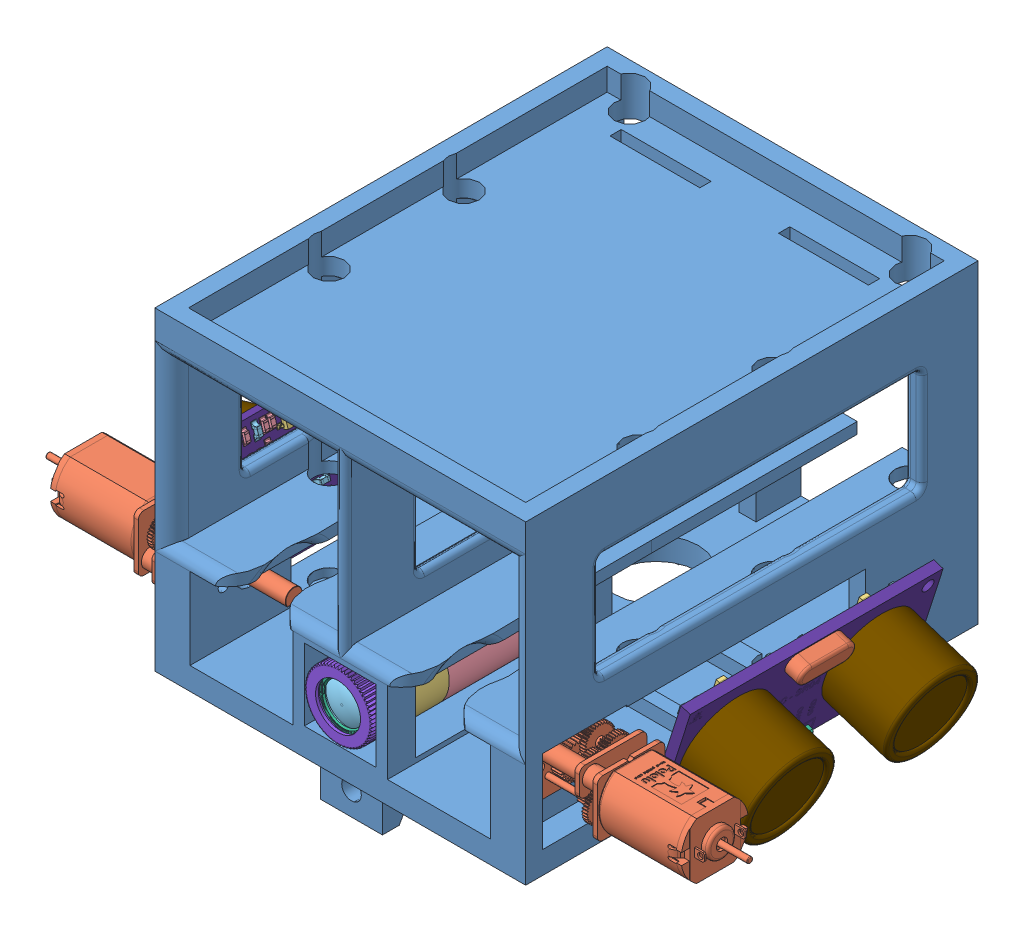
SolidWorks assembly ZumoPlatform, configuration Default. Lengths in mm.
Overall size (124.9 63 80.53).
123 component instances, 24 part files, 37 mates.
Components (placement in the parent):
- Platform-1: Platform [Default] at (31.3315 31.2801 62.3209) size (66.46 63 80.5)
- micro-metal-gearmotor-1000-backshaft-1: micro-metal-gearmotor-1000-backshaft [Default] at (72.5815 44.5801 92.0709) x (0 0 1) z (-1 0 0) size (12.01 10.08 43.7)
- micro-metal-gearmotor-1000-backshaft-2: micro-metal-gearmotor-1000-backshaft [Default] at (-9.9185 44.5801 92.0709) x (0 0 1) z (1 0 0) size (12.01 10.08 43.7)
- Laser Diode Module-1: Laser Diode Module [Default] at (1.0789 32.0697 83.277) x (-0.999994 0.003569 0) z (0.003569 0.999994 0) size (12.77 59.55 13.15)
  - LD module diode mount back nut-1: LD module diode mount back nut [Default] at (-29.8165 5.6939 10.1669) size (12 16.05 12.21)
  - LD module body-1: LD module body [Default] at (-29.8165 -14.5006 10.1669) x (0.999982 0 -0.006001) z (0.006001 0 0.999982) size (12 20.05 13.08)
  - G-2 colimating lens-1: G-2 colimating lens [Default] at (-29.9063 12.9338 10.1669) size (8.06 5.78 8.06)
  - G-2 lens focusable mount-1: G-2 lens focusable mount [Default] at (-29.9063 10.9338 10.1669) x (0.993643 0 0.112577) z (-0.112577 0 0.993643) size (9.01 8.01 10.39)
  - LD module tension spring-2: LD module tension spring [Default] at (-29.8165 10.9338 10.1669) size (8.46 6.4 9.76)
  - Lens Focusing Ring-1: Lens Focusing Ring [Default] at (-29.8165 15.7939 10.1669) x (-0.998124 0 -0.061226) z (0 1 0) size (12.06 12.06 3.9)
  - Mitsubishi ML501P73 500mW 638nm Laser Diode with leads-1: Mitsubishi ML501P73 500mW 638nm Laser Diode with leads [Default] at (-29.8165 0.2494 10.1669) x (0.917172 0 0.398492) z (-0.398492 0 0.917172) size (5.58 43.98 5.49)
- slc_connector_811-s1-006-10-014101-1: slc_connector_811-s1-006-10-014101 [Default] at (46.7115 79.0101 31.9709) x (1 0 0) z (0 -1 0) size (15.24 9 2.54)
  - slc_connector_811-s1-006-10-014101_01-1: slc_connector_811-s1-006-10-014101_01 [Default] at origin size (15.24 7.5 2.54)
  - slc_connector_811-s1-006-10-014101_02-1: slc_connector_811-s1-006-10-014101_02 [Default] at origin size (1.25 4.17 1.25)
  - slc_connector_811-s1-006-10-014101_03-1: slc_connector_811-s1-006-10-014101_03 [Default] at origin size (1.25 4.17 1.25)
  - slc_connector_811-s1-006-10-014101_04-1: slc_connector_811-s1-006-10-014101_04 [Default] at origin size (1.25 4.17 1.25)
  - slc_connector_811-s1-006-10-014101_05-1: slc_connector_811-s1-006-10-014101_05 [Default] at origin size (1.25 4.17 1.25)
  - slc_connector_811-s1-006-10-014101_06-1: slc_connector_811-s1-006-10-014101_06 [Default] at origin size (1.25 4.17 1.25)
  - slc_connector_811-s1-006-10-014101_07-1: slc_connector_811-s1-006-10-014101_07 [Default] at origin size (1.25 4.17 1.25)
- slc_connector_811-s1-006-10-014101-2: slc_connector_811-s1-006-10-014101 [Default] at (15.9515 79.0101 31.9709) x (1 0 0) z (0 -1 0) size (15.24 9 2.54)
  - slc_connector_811-s1-006-10-014101_01-1: slc_connector_811-s1-006-10-014101_01 [Default] at origin size (15.24 7.5 2.54)
  - slc_connector_811-s1-006-10-014101_02-1: slc_connector_811-s1-006-10-014101_02 [Default] at origin size (1.25 4.17 1.25)
  - slc_connector_811-s1-006-10-014101_03-1: slc_connector_811-s1-006-10-014101_03 [Default] at origin size (1.25 4.17 1.25)
  - slc_connector_811-s1-006-10-014101_04-1: slc_connector_811-s1-006-10-014101_04 [Default] at origin size (1.25 4.17 1.25)
  - slc_connector_811-s1-006-10-014101_05-1: slc_connector_811-s1-006-10-014101_05 [Default] at origin size (1.25 4.17 1.25)
  - slc_connector_811-s1-006-10-014101_06-1: slc_connector_811-s1-006-10-014101_06 [Default] at origin size (1.25 4.17 1.25)
  - slc_connector_811-s1-006-10-014101_07-1: slc_connector_811-s1-006-10-014101_07 [Default] at origin size (1.25 4.17 1.25)
- HC-SR04-1: HC-SR04 [Default] at (-5.6368 33.7192 38.4111) x (0 0 1) z (-0.957373 -0.288853 0) size (45 20.53 19.69)
  - HC-SR04_HC-SR04 Ping Sensor-1: HC-SR04_HC-SR04 Ping Sensor [Default] at (22.5 10.25 -1.75) x (0 -1 0) z (0 0 1) size (20.53 45 15.35)
    - HC-SR04_PCB-1: HC-SR04_PCB [Default] at origin size (20.53 45 1.75)
    - HC-SR04_Transducer-1: HC-SR04_Transducer [Default] at (0 -13.16 13.25) x (1 0 0) z (0 -1 0) size (15.88 12 15.88)
    - HC-SR04_Transducer-2: HC-SR04_Transducer [Default] at (0 12.34 13.25) x (1 0 0) z (0 -1 0) size (15.88 12 15.88)
    - HC-SR04_14 Pin SMT-1: HC-SR04_14 Pin SMT [Default] at (0 17.5274 -0.85) x (1 0 0) z (0 1 0) size (6 1.6 8.8)
    - HC-SR04_14 Pin SMT-2: HC-SR04_14 Pin SMT [Default] at (-0.35 -18.5 -0.85) x (0 -1 0) z (1 0 0) size (6 1.6 8.8)
    - HC-SR04_14 Pin SMT-3: HC-SR04_14 Pin SMT [Default] at (0 -0.3826 -0.85) x (1 0 0) z (0 1 0) size (6 1.6 8.8)
    - HC-SR04_HC-SR04 Crystal-1: HC-SR04_HC-SR04 Crystal [Default] at (-8.3 0 1.75) x (0 -1 0) z (0 0 1) size (10 3.5 2.7)
    - HC-SR04_ssot3-1: HC-SR04_ssot3 [Default] at (-7.9706 11.2297 0) x (1 0 0) z (0 1 0) size (3 1.13 3.09)
    - HC-SR04_ssot3-2: HC-SR04_ssot3 [Default] at (-7.9706 -14.2327 0) x (1 0 0) z (0 1 0) size (3 1.13 3.09)
    - HC-SR04_MLC0603-1: HC-SR04_MLC0603 [Default] at (1.5086 11.2209 0) x (1 0 0) z (0 1 0) size (2.36 0.6 1.03)
    - HC-SR04_MLC0603-2: HC-SR04_MLC0603 [Default] at (-4.7079 -6.8438 0) x (1 0 0) z (0 1 0) size (2.36 0.6 1.03)
    - HC-SR04_MLC0603-3: HC-SR04_MLC0603 [Default] at (-8.4554 -9.9341 0) x (0 1 0) z (-1 0 0) size (2.36 0.6 1.03)
    - HC-SR04_MLC0603-4: HC-SR04_MLC0603 [Default] at (7.7901 17.1702 0) x (1 0 0) z (0 1 0) size (2.36 0.6 1.03)
    - HC-SR04_MLC0603-5: HC-SR04_MLC0603 [Default] at (-4.2399 7.0151 0) x (0 1 0) z (-1 0 0) size (2.36 0.6 1.03)
    - HC-SR04_MLC0603-6: HC-SR04_MLC0603 [Default] at (-8.2266 4.8481 0) x (1 0 0) z (0 1 0) size (2.36 0.6 1.03)
    - HC-SR04_MLC0603-7: HC-SR04_MLC0603 [Default] at (-8.276 3.0726 0) x (1 0 0) z (0 1 0) size (2.36 0.6 1.03)
    - HC-SR04_MLC0603-8: HC-SR04_MLC0603 [Default] at (-8.1718 18.0917 0) x (1 0 0) z (0 1 0) size (2.36 0.6 1.03)
    - HC-SR04_MLC0603-9: HC-SR04_MLC0603 [Default] at (-5.0505 19.9858 0) x (0 1 0) z (-1 0 0) size (2.36 0.6 1.03)
    - HC-SR04_MLC0603-10: HC-SR04_MLC0603 [Default] at (4.9221 -0.625 0) x (0 1 0) z (-1 0 0) size (2.36 0.6 1.03)
    - HC-SR04_MLC0603-11: HC-SR04_MLC0603 [Default] at (-6.3425 7.0242 0) x (0 1 0) z (-1 0 0) size (2.36 0.6 1.03)
    - HC-SR04_MLC0603-12: HC-SR04_MLC0603 [Default] at (4.867 -3.8906 0) x (0 1 0) z (-1 0 0) size (2.36 0.6 1.03)
    - HC-SR04_MLC0603-13: HC-SR04_MLC0603 [Default] at (7.7433 15.7761 0) x (1 0 0) z (0 1 0) size (2.36 0.6 1.03)
    - HC-SR04_MLC0603-14: HC-SR04_MLC0603 [Default] at (0.771 7.4861 0) x (0 1 0) z (-1 0 0) size (2.36 0.6 1.03)
    - HC-SR04_MLC0603-15: HC-SR04_MLC0603 [Default] at (-5.1303 17.0114 0) x (0 1 0) z (-1 0 0) size (2.36 0.6 1.03)
    - HC-SR04_MLC0603-16: HC-SR04_MLC0603 [Default] at (-8.2323 14.696 0) x (1 0 0) z (0 1 0) size (2.36 0.6 1.03)
    - HC-SR04_MLC0603-17: HC-SR04_MLC0603 [Default] at (7.5824 9.9685 0) x (1 0 0) z (0 1 0) size (2.36 0.6 1.03)
    - HC-SR04_MLC0603-18: HC-SR04_MLC0603 [Default] at (-8.2128 13.4796 0) x (1 0 0) z (0 1 0) size (2.36 0.6 1.03)
    - HC-SR04_MLC0603-19: HC-SR04_MLC0603 [Default] at (-5.1791 14.6881 0) x (1 0 0) z (0 1 0) size (2.36 0.6 1.03)
    - HC-SR04_MLC0603-20: HC-SR04_MLC0603 [Default] at (-2.0926 7.3723 0) x (1 0 0) z (0 1 0) size (2.36 0.6 1.03)
    - HC-SR04_603 cap on pad-1: HC-SR04_603 cap on pad [Default] at (-1.0221 -11.2109 0) x (0 1 0) z (-1 0 0) size (2.76 0.9 1.12)
    - HC-SR04_603 cap on pad-2: HC-SR04_603 cap on pad [Default] at (-8.0142 0.0287 0) x (1 0 0) z (0 1 0) size (2.76 0.9 1.12)
    - HC-SR04_603 cap on pad-3: HC-SR04_603 cap on pad [Default] at (-1.0582 -6.7842 0) x (1 0 0) z (0 1 0) size (2.76 0.9 1.12)
    - HC-SR04_603 cap on pad-4: HC-SR04_603 cap on pad [Default] at (8.2921 12.7142 0) x (0 1 0) z (-1 0 0) size (2.76 0.9 1.12)
    - HC-SR04_603 cap on pad-5: HC-SR04_603 cap on pad [Default] at (-2.0106 11.2331 0) x (1 0 0) z (0 1 0) size (2.76 0.9 1.12)
    - HC-SR04_603 cap on pad-6: HC-SR04_603 cap on pad [Default] at (4.491 7.5361 0) x (0 1 0) z (-1 0 0) size (2.76 0.9 1.12)
    - HC-SR04_603 cap on pad-7: HC-SR04_603 cap on pad [Default] at (-7.8611 -20.9225 0) x (1 0 0) z (0 1 0) size (2.76 0.9 1.12)
    - HC-SR04_603 cap on pad-8: HC-SR04_603 cap on pad [Default] at (-7.8553 -18.6213 0) x (1 0 0) z (0 1 0) size (2.76 0.9 1.12)
    - HC-SR04_603 cap on pad-9: HC-SR04_603 cap on pad [Default] at (2.5708 7.5761 0) x (0 1 0) z (-1 0 0) size (2.76 0.9 1.12)
    - HC-SR04_603 cap on pad-10: HC-SR04_603 cap on pad [Default] at (5.7718 -17.5016 0) x (0 1 0) z (-1 0 0) size (2.76 0.9 1.12)
    - HC-SR04_603 cap on pad-11: HC-SR04_603 cap on pad [Default] at (-8.071 -5.768 0) x (1 0 0) z (0 1 0) size (2.76 0.9 1.12)
    - HC-SR04_603 cap on pad-12: HC-SR04_603 cap on pad [Default] at (7.8006 20.8278 0) x (1 0 0) z (0 1 0) size (2.76 0.9 1.12)
    - HC-SR04_603 cap on pad-13: HC-SR04_603 cap on pad [Default] at (-8.1408 16.1462 0) x (1 0 0) z (0 1 0) size (2.76 0.9 1.12)
    - HC-SR04_603 cap on pad-14: HC-SR04_603 cap on pad [Default] at (7.8006 18.9728 0) x (1 0 0) z (0 1 0) size (2.76 0.9 1.12)
    - HC-SR04_603 cap on pad-15: HC-SR04_603 cap on pad [Default] at (-2.0811 9.4105 0) x (1 0 0) z (0 1 0) size (2.76 0.9 1.12)
    - HC-SR04_603 cap on pad-16: HC-SR04_603 cap on pad [Default] at (0.9766 -11.2109 0) x (0 1 0) z (-1 0 0) size (2.76 0.9 1.12)
  - Header Vertical 2_54mm Pitch2-14 Way-1: Header Vertical 2_54mm Pitch2-14 Way [4 Way] at (19.9998 2.8881 -1.75) x (0 -1 0) z (1 0 0) size (2.54 8.88 10.16)
- HC-SR04-2: HC-SR04 [Default] at (68.2708 33.6477 83.4906) x (0 0 -1) z (0.95199 -0.30613 0) size (45 20.53 19.69)
  - HC-SR04_HC-SR04 Ping Sensor-1: HC-SR04_HC-SR04 Ping Sensor [Default] at (22.5 10.25 -1.75) x (0 -1 0) z (0 0 1) size (20.53 45 15.35)
    - HC-SR04_PCB-1: HC-SR04_PCB [Default] at origin size (20.53 45 1.75)
    - HC-SR04_Transducer-1: HC-SR04_Transducer [Default] at (0 -13.16 13.25) x (1 0 0) z (0 -1 0) size (15.88 12 15.88)
    - HC-SR04_Transducer-2: HC-SR04_Transducer [Default] at (0 12.34 13.25) x (1 0 0) z (0 -1 0) size (15.88 12 15.88)
    - HC-SR04_14 Pin SMT-1: HC-SR04_14 Pin SMT [Default] at (0 17.5274 -0.85) x (1 0 0) z (0 1 0) size (6 1.6 8.8)
    - HC-SR04_14 Pin SMT-2: HC-SR04_14 Pin SMT [Default] at (-0.35 -18.5 -0.85) x (0 -1 0) z (1 0 0) size (6 1.6 8.8)
    - HC-SR04_14 Pin SMT-3: HC-SR04_14 Pin SMT [Default] at (0 -0.3826 -0.85) x (1 0 0) z (0 1 0) size (6 1.6 8.8)
    - HC-SR04_HC-SR04 Crystal-1: HC-SR04_HC-SR04 Crystal [Default] at (-8.3 0 1.75) x (0 -1 0) z (0 0 1) size (10 3.5 2.7)
    - HC-SR04_ssot3-1: HC-SR04_ssot3 [Default] at (-7.9706 11.2297 0) x (1 0 0) z (0 1 0) size (3 1.13 3.09)
    - HC-SR04_ssot3-2: HC-SR04_ssot3 [Default] at (-7.9706 -14.2327 0) x (1 0 0) z (0 1 0) size (3 1.13 3.09)
    - HC-SR04_MLC0603-1: HC-SR04_MLC0603 [Default] at (1.5086 11.2209 0) x (1 0 0) z (0 1 0) size (2.36 0.6 1.03)
    - HC-SR04_MLC0603-2: HC-SR04_MLC0603 [Default] at (-4.7079 -6.8438 0) x (1 0 0) z (0 1 0) size (2.36 0.6 1.03)
    - HC-SR04_MLC0603-3: HC-SR04_MLC0603 [Default] at (-8.4554 -9.9341 0) x (0 1 0) z (-1 0 0) size (2.36 0.6 1.03)
    - HC-SR04_MLC0603-4: HC-SR04_MLC0603 [Default] at (7.7901 17.1702 0) x (1 0 0) z (0 1 0) size (2.36 0.6 1.03)
    - HC-SR04_MLC0603-5: HC-SR04_MLC0603 [Default] at (-4.2399 7.0151 0) x (0 1 0) z (-1 0 0) size (2.36 0.6 1.03)
    - HC-SR04_MLC0603-6: HC-SR04_MLC0603 [Default] at (-8.2266 4.8481 0) x (1 0 0) z (0 1 0) size (2.36 0.6 1.03)
    - HC-SR04_MLC0603-7: HC-SR04_MLC0603 [Default] at (-8.276 3.0726 0) x (1 0 0) z (0 1 0) size (2.36 0.6 1.03)
    - HC-SR04_MLC0603-8: HC-SR04_MLC0603 [Default] at (-8.1718 18.0917 0) x (1 0 0) z (0 1 0) size (2.36 0.6 1.03)
    - HC-SR04_MLC0603-9: HC-SR04_MLC0603 [Default] at (-5.0505 19.9858 0) x (0 1 0) z (-1 0 0) size (2.36 0.6 1.03)
    - HC-SR04_MLC0603-10: HC-SR04_MLC0603 [Default] at (4.9221 -0.625 0) x (0 1 0) z (-1 0 0) size (2.36 0.6 1.03)
    - HC-SR04_MLC0603-11: HC-SR04_MLC0603 [Default] at (-6.3425 7.0242 0) x (0 1 0) z (-1 0 0) size (2.36 0.6 1.03)
    - HC-SR04_MLC0603-12: HC-SR04_MLC0603 [Default] at (4.867 -3.8906 0) x (0 1 0) z (-1 0 0) size (2.36 0.6 1.03)
    - HC-SR04_MLC0603-13: HC-SR04_MLC0603 [Default] at (7.7433 15.7761 0) x (1 0 0) z (0 1 0) size (2.36 0.6 1.03)
    - HC-SR04_MLC0603-14: HC-SR04_MLC0603 [Default] at (0.771 7.4861 0) x (0 1 0) z (-1 0 0) size (2.36 0.6 1.03)
    - HC-SR04_MLC0603-15: HC-SR04_MLC0603 [Default] at (-5.1303 17.0114 0) x (0 1 0) z (-1 0 0) size (2.36 0.6 1.03)
    - HC-SR04_MLC0603-16: HC-SR04_MLC0603 [Default] at (-8.2323 14.696 0) x (1 0 0) z (0 1 0) size (2.36 0.6 1.03)
    - HC-SR04_MLC0603-17: HC-SR04_MLC0603 [Default] at (7.5824 9.9685 0) x (1 0 0) z (0 1 0) size (2.36 0.6 1.03)
    - HC-SR04_MLC0603-18: HC-SR04_MLC0603 [Default] at (-8.2128 13.4796 0) x (1 0 0) z (0 1 0) size (2.36 0.6 1.03)
    - HC-SR04_MLC0603-19: HC-SR04_MLC0603 [Default] at (-5.1791 14.6881 0) x (1 0 0) z (0 1 0) size (2.36 0.6 1.03)
    - HC-SR04_MLC0603-20: HC-SR04_MLC0603 [Default] at (-2.0926 7.3723 0) x (1 0 0) z (0 1 0) size (2.36 0.6 1.03)
    - HC-SR04_603 cap on pad-1: HC-SR04_603 cap on pad [Default] at (-1.0221 -11.2109 0) x (0 1 0) z (-1 0 0) size (2.76 0.9 1.12)
    - HC-SR04_603 cap on pad-2: HC-SR04_603 cap on pad [Default] at (-8.0142 0.0287 0) x (1 0 0) z (0 1 0) size (2.76 0.9 1.12)
    - HC-SR04_603 cap on pad-3: HC-SR04_603 cap on pad [Default] at (-1.0582 -6.7842 0) x (1 0 0) z (0 1 0) size (2.76 0.9 1.12)
    - HC-SR04_603 cap on pad-4: HC-SR04_603 cap on pad [Default] at (8.2921 12.7142 0) x (0 1 0) z (-1 0 0) size (2.76 0.9 1.12)
    - HC-SR04_603 cap on pad-5: HC-SR04_603 cap on pad [Default] at (-2.0106 11.2331 0) x (1 0 0) z (0 1 0) size (2.76 0.9 1.12)
    - HC-SR04_603 cap on pad-6: HC-SR04_603 cap on pad [Default] at (4.491 7.5361 0) x (0 1 0) z (-1 0 0) size (2.76 0.9 1.12)
    - HC-SR04_603 cap on pad-7: HC-SR04_603 cap on pad [Default] at (-7.8611 -20.9225 0) x (1 0 0) z (0 1 0) size (2.76 0.9 1.12)
    - HC-SR04_603 cap on pad-8: HC-SR04_603 cap on pad [Default] at (-7.8553 -18.6213 0) x (1 0 0) z (0 1 0) size (2.76 0.9 1.12)
    - HC-SR04_603 cap on pad-9: HC-SR04_603 cap on pad [Default] at (2.5708 7.5761 0) x (0 1 0) z (-1 0 0) size (2.76 0.9 1.12)
    - HC-SR04_603 cap on pad-10: HC-SR04_603 cap on pad [Default] at (5.7718 -17.5016 0) x (0 1 0) z (-1 0 0) size (2.76 0.9 1.12)
    - HC-SR04_603 cap on pad-11: HC-SR04_603 cap on pad [Default] at (-8.071 -5.768 0) x (1 0 0) z (0 1 0) size (2.76 0.9 1.12)
    - HC-SR04_603 cap on pad-12: HC-SR04_603 cap on pad [Default] at (7.8006 20.8278 0) x (1 0 0) z (0 1 0) size (2.76 0.9 1.12)
    - HC-SR04_603 cap on pad-13: HC-SR04_603 cap on pad [Default] at (-8.1408 16.1462 0) x (1 0 0) z (0 1 0) size (2.76 0.9 1.12)
    - HC-SR04_603 cap on pad-14: HC-SR04_603 cap on pad [Default] at (7.8006 18.9728 0) x (1 0 0) z (0 1 0) size (2.76 0.9 1.12)
    - HC-SR04_603 cap on pad-15: HC-SR04_603 cap on pad [Default] at (-2.0811 9.4105 0) x (1 0 0) z (0 1 0) size (2.76 0.9 1.12)
    - HC-SR04_603 cap on pad-16: HC-SR04_603 cap on pad [Default] at (0.9766 -11.2109 0) x (0 1 0) z (-1 0 0) size (2.76 0.9 1.12)
  - Header Vertical 2_54mm Pitch2-14 Way-1: Header Vertical 2_54mm Pitch2-14 Way [4 Way] at (19.9998 2.8881 -1.75) x (0 -1 0) z (1 0 0) size (2.54 8.88 10.16)
Mates (geometry in assembly coordinates):
- Coincident6: coincident anti-aligned: plane of Platform-1 through (1.3315 80.2801 22.0709) normal (1 0 0); plane of ? through (1.3315 79.7801 116.9853) normal (-1 0 0)
- Coincident7: coincident anti-aligned: plane of Platform-1 through (19.6164 51.7801 94.5774) normal (0 1 0); plane of ? through (29.3315 51.7801 116.9853) normal (0 -1 0)
- Concentric1: concentric anti-aligned: cylinder of Platform-1 through (64.3325 44.5801 92.0709) axis (-1 0 0) radius 2.5; cylinder of micro-metal-gearmotor-1000-backshaft-2 through (7.0815 44.5801 92.0709) axis (1 0 0) radius 1.5
- Concentric2: concentric aligned: cylinder of Platform-1 through (64.3325 44.5801 87.5709) axis (-1 0 0) radius 1; cylinder of micro-metal-gearmotor-1000-backshaft-2 through (2.1815 44.5801 87.5709) axis (-1 0 0) radius 0.8
- Coincident8: coincident anti-aligned: plane of Platform-1 through (2.5815 49.7801 62.3209) normal (-1 0 0); plane of micro-metal-gearmotor-1000-backshaft-2 through (2.5815 39.5801 86.0709) normal (1 0 0)
- Concentric3: concentric aligned: cylinder of Platform-1 through (64.3325 44.5801 92.0709) axis (-1 0 0) radius 2.5; cylinder of micro-metal-gearmotor-1000-backshaft-1 through (55.5815 44.5801 92.0709) axis (-1 0 0) radius 1.5
- Concentric4: concentric anti-aligned: cylinder of Platform-1 through (64.3325 44.5801 87.5709) axis (-1 0 0) radius 1; cylinder of micro-metal-gearmotor-1000-backshaft-1 through (60.4815 44.5801 87.5709) axis (1 0 0) radius 0.8
- Coincident9: coincident anti-aligned: plane of Platform-1 through (60.0815 49.7801 62.3209) normal (1 0 0); plane of micro-metal-gearmotor-1000-backshaft-1 through (60.0815 49.5801 86.0709) normal (-1 0 0)
- Coincident11: coincident anti-aligned: plane of Platform-1 through (19.6164 51.7801 94.5774) normal (0 1 0); plane of ? through (61.3315 51.7801 118.8205) normal (0 -1 0)
- Coincident12: coincident anti-aligned: plane of Platform-1 through (61.3315 80.2801 22.0709) normal (-1 0 0); plane of ? through (61.3315 79.7801 118.8205) normal (1 0 0)
- Coincident13: coincident anti-aligned: plane of ? through (47.3315 77.0801 159.0705) normal (0 1 0); plane of ? through (54.5158 77.0801 135.8022) normal (0 -1 0)
- Coincident14: coincident anti-aligned: plane of ? through (15.3315 77.0801 157.2353) normal (0 1 0); plane of ? through (22.5158 77.0801 133.967) normal (0 -1 0)
- Tangent3: tangent anti-aligned: plane of ? through (39.5815 77.0801 138.8205) normal (0 0 -1); cylinder of ? through (53.5515 83.5868 138.5919) axis (0 1 0) radius 0.2286
- Tangent4: tangent anti-aligned: plane of ? through (7.5815 77.0801 136.9853) normal (0 0 -1); cylinder of ? through (21.5515 83.5868 136.7567) axis (0 1 0) radius 0.2286
- Coincident15: coincident anti-aligned: plane of ? through (7.5815 77.0801 116.9853) normal (1 0 0); plane of ? through (7.5815 79.2201 133.967) normal (-1 0 0)
- Coincident16: coincident anti-aligned: plane of ? through (39.5815 77.0801 118.8205) normal (1 0 0); plane of ? through (39.5815 79.2201 135.8022) normal (-1 0 0)
- Coincident17: coincident anti-aligned: plane of Platform-1 through (31.3315 80.2801 62.3209) normal (0 -1 0); plane of slc_connector_811-s1-006-10-014101-1/slc_connector_811-s1-006-10-014101_01-1 through (39.278 80.2801 35.9709) normal (0 1 0)
- Coincident18: coincident anti-aligned: plane of Platform-1 through (31.3315 80.2801 62.3209) normal (0 -1 0); plane of slc_connector_811-s1-006-10-014101-2/slc_connector_811-s1-006-10-014101_01-1 through (8.518 80.2801 35.9709) normal (0 1 0)
- Coincident20: coincident anti-aligned: plane of Platform-1 through (54.3315 28.7791 29.5709) normal (-1 0 0); plane of slc_connector_811-s1-006-10-014101-1/slc_connector_811-s1-006-10-014101_01-1 through (54.3315 79.8801 35.9709) normal (1 0 0)
- Coincident21: coincident anti-aligned: plane of Platform-1 through (8.3315 28.7791 29.5709) normal (1 0 0); plane of slc_connector_811-s1-006-10-014101-2/slc_connector_811-s1-006-10-014101_01-1 through (8.3315 78.1401 35.9709) normal (-1 0 0)
- Coincident22: coincident aligned: plane of Platform-1 through (8.3315 28.7791 31.5709) normal (0 0 -1); plane of slc_connector_811-s1-006-10-014101-2/slc_connector_811-s1-006-10-014101_01-1 through (10.1015 79.0101 31.5709) normal (0 0 -1)
- Coincident23: coincident aligned: plane of Platform-1 through (38.3315 28.7791 31.5709) normal (0 0 -1); plane of slc_connector_811-s1-006-10-014101-1/slc_connector_811-s1-006-10-014101_01-1 through (53.5615 79.0101 31.5709) normal (0 0 -1)
- LimitDistance1: limit distance = 97.0373 mm anti-aligned: plane of ? through (54.5158 79.6201 133.0082) normal (0 0 -1); plane of slc_connector_811-s1-006-10-014101-1/slc_connector_811-s1-006-10-014101_01-1 through (38.0936 80.2801 35.9709) normal (0 0 1)
- LimitDistance2: limit distance = 86.0789 mm anti-aligned: plane of ? through (22.5158 79.6201 122.0498) normal (0 0 -1); plane of slc_connector_811-s1-006-10-014101-2/slc_connector_811-s1-006-10-014101_01-1 through (7.3336 80.2801 35.9709) normal (0 0 1)
- Coincident25: coincident anti-aligned: plane of Platform-1 through (1.3315 80.2801 22.0709) normal (1 0 0); plane of ? through (1.3315 79.7801 102.2832) normal (-1 0 0)
- Coincident26: coincident anti-aligned: plane of Platform-1 through (19.6164 51.7801 94.5774) normal (0 1 0); plane of ? through (1.3315 51.7801 102.2832) normal (0 -1 0)
- Coincident27: coincident anti-aligned: plane of Platform-1 through (19.6164 51.7801 94.5774) normal (0 1 0); plane of ? through (33.3315 51.7801 102.2832) normal (0 -1 0)
- Coincident28: coincident anti-aligned: plane of Platform-1 through (61.3315 80.2801 22.0709) normal (-1 0 0); plane of ? through (61.3315 79.7801 102.2832) normal (1 0 0)
- LimitDistance3: limit distance = 0 mm anti-aligned: plane of slc_connector_811-s1-006-10-014101-2/slc_connector_811-s1-006-10-014101_01-1 through (7.3336 80.2801 35.9709) normal (0 0 1); plane of ? through (22.7758 79.6201 35.9709) normal (0 0 -1)
- LimitDistance4: limit distance = 0 mm anti-aligned: plane of ? through (54.7758 79.6201 35.9709) normal (0 0 -1); plane of slc_connector_811-s1-006-10-014101-1/slc_connector_811-s1-006-10-014101_01-1 through (38.0936 80.2801 35.9709) normal (0 0 1)
- Coincident29: coincident aligned: plane of Platform-1 through (-1.6685 35.2801 102.5709) normal (0 0 1); plane of Laser Diode Module-1/Lens Focusing Ring-1 through (30.9315 42.1301 102.5709) normal (0 0 1)
- Tangent5: tangent anti-aligned: cylinder of Laser Diode Module-1/LD module diode mount back nut-1 through (30.9315 42.1301 88.7764) axis (0 0 1) radius 6; plane of Platform-1 through (37.7315 36.1301 62.5709) normal (0 1 0)
- Tangent6: tangent anti-aligned: cylinder of Laser Diode Module-1/LD module diode mount back nut-1 through (30.9315 42.1301 88.7764) axis (0 0 1) radius 6; plane of Platform-1 through (24.9315 48.9301 62.5709) normal (1 0 0)
- Coincident30: coincident anti-aligned: line of Platform-1 through (64.3315 35.2801 66.3709) axis (0 0 -1); line of HC-SR04-2/Header Vertical 2_54mm Pitch2-14 Way-1 through (64.3315 35.2801 58.7109) axis (0 0 1)
- Coincident31: coincident anti-aligned: line of Platform-1 through (-1.6685 35.2801 55.8709) axis (0 0 1); line of HC-SR04-1/Header Vertical 2_54mm Pitch2-14 Way-1 through (-1.6685 35.2801 63.1909) axis (0 0 -1)
- Coincident32: coincident anti-aligned: plane of Platform-1 through (31.3315 37.7801 55.8709) normal (0 0 1); plane of HC-SR04-2/Header Vertical 2_54mm Pitch2-14 Way-1 through (65.0172 37.4126 55.8709) normal (0 0 -1)
- Coincident33: coincident anti-aligned: plane of Platform-1 through (31.3315 37.7801 55.8709) normal (0 0 1); plane of HC-SR04-1/Header Vertical 2_54mm Pitch2-14 Way-1 through (-1.7552 35.5674 55.8709) normal (0 0 -1)
